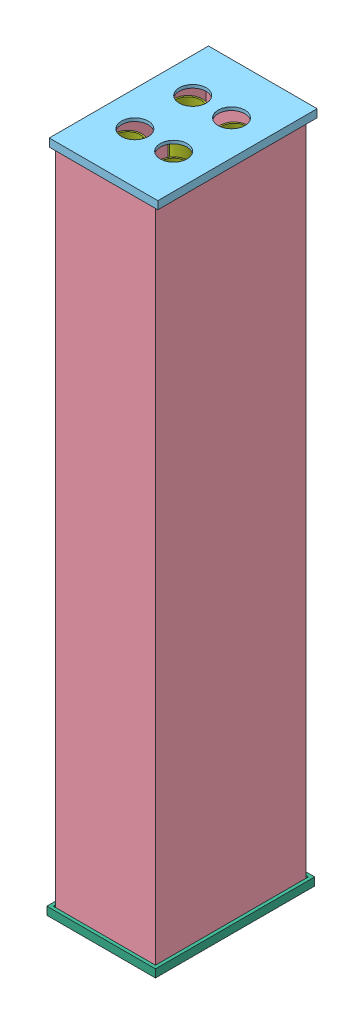
SolidWorks assembly Ensamblaje1, configuration Predeterminado. Lengths in mm.
Overall size (68.5 429 102).
50 component instances, 27 part files, 116 mates.
Components (placement in the parent):
- ServosConTubos-1: ServosConTubos [Predeterminado] at (2.491 9.9258 73.5) size (49 4 78)
- UnionTubos-1: UnionTubos [Predeterminado] at (2.491 9.9258 75.55) x (-1 0 0) z (0 0 1) size (49 40.94 58.1)
- Servo-1: Servo [Predeterminado] at (2.741 -2.0742 52.75) size (12 30.1 32.5)
- Servo-2: Servo [Predeterminado] at (2.741 -2.0742 91.25) size (12 30.1 32.5)
- Acrilico-1: Acrilico [Predeterminado] at (1.741 -24.0149 74.8) x (-1 0 0) z (0 0 -1) size (63 420 95) (hidden)
- ServosConTubos-2: ServosConTubos [Predeterminado] at (2.491 75.8429 73.5) x (-1 0 0) z (0 0 1) size (49 4 78)
- Servo-3: Servo [Predeterminado] at (2.241 87.8429 52.75) x (-1 0 0) z (0 0 1) size (12 30.1 32.5)
- Servo-4: Servo [Predeterminado] at (2.241 87.8429 91.25) x (-1 0 0) z (0 0 1) size (12 30.1 32.5)
- SoporteTubos-1: SoporteTubos [Predeterminado] at (-5.259 395.9851 62.8) size (68.5 5 100.5)
- TubosMedio-1: TubosMedio [Predeterminado] at (2.491 53.6258 73.5) size (49 2 78)
- Perno-1: Perno [Predeterminado] at (21.991 75.8429 41.5) size (8.7 78.2 8.7)
- Perno-2: Perno [Predeterminado] at (-17.009 75.8429 41.5) size (8.7 78.2 8.7)
- Perno-3: Perno [Predeterminado] at (21.991 75.8429 109.5) x (0.404197 0 -0.914672) z (0.914672 0 0.404197) size (8.7 78.2 8.7) (hidden)
- Perno-4: Perno [Predeterminado] at (-17.009 75.8429 109.5) x (-0.888519 0 0.45884) z (-0.45884 0 -0.888519) size (8.7 78.2 8.7) (hidden)
- PastillaAmarrillaAjuste-1: PastillaAmarrillaAjuste [Predeterminado] at (-12.009 64.3429 94.6) x (0 0 1) z (-1 0 0) size (20 15.85 18)
- PernoTuerca-1: PernoTuerca [Predeterminado] at (-17.009 6.4258 41.5) x (0.998119 0 0.061298) z (-0.061298 0 0.998119) size (9.5 3.5 10.97)
- PernoTuerca-2: PernoTuerca [Predeterminado] at (21.991 6.4258 109.5) size (9.5 3.5 10.97)
- PernoTuerca-3: PernoTuerca [Predeterminado] at (-17.009 6.4258 109.5) x (0.996539 0 -0.083129) z (0.083129 0 0.996539) size (9.5 3.5 10.97)
- PernoTuerca-4: PernoTuerca [Predeterminado] at (21.991 6.4258 41.5) size (9.5 3.5 10.97)
- TuboMedioAmarrillo-1: TuboMedioAmarrillo [Predeterminado] at (-12.009 29.6258 94.6) x (0.872551 0 -0.488522) z (0.488522 0 0.872551) size (14.5 26 14.5)
- PastillaAmarrillaAjuste-2: PastillaAmarrillaAjuste [Predeterminado] at (-12.009 21.4258 94.6) x (0 0 -1) z (-1 0 0) size (20 15.85 18) (hidden)
- PastillaBlancaAjuste-2: PastillaBlancaAjuste [Predeterminado] at (16.991 21.4258 94.6) x (0 0 1) z (1 0 0) size (20 20.07 18) (hidden)
- TuboMedioBlanco-1: TuboMedioBlanco [Predeterminado] at (16.991 34.1258 94.6) x (0.999102 0 -0.042366) z (0.042366 0 0.999102) size (12.5 21.5 12.5)
- PastillaBlancaAjuste2-1: PastillaBlancaAjuste2 [Predeterminado] at (16.991 64.3429 94.6) x (0 0 -1) z (1 0 0) size (20 15.53 18)
- PastillaNaranjaAjuste-1: PastillaNaranjaAjuste [Predeterminado] at (16.991 64.3429 56.5) x (0 0 -1) z (1 0 0) size (20 15.72 18)
- TuboMedioNaranja-1: TuboMedioNaranja [Predeterminado] at (16.991 36.1258 56.5) size (15 19.5 15)
- TuboMedioAzul-1: TuboMedioAzul [Predeterminado] at (-12.009 36.1258 56.5) x (-0.835913 0 0.548862) z (-0.548862 0 -0.835913) size (13 19.5 13)
- PastillaAzulAjuste-1: PastillaAzulAjuste [Predeterminado] at (-12.009 64.3429 56.5) x (0 0 1) z (-1 0 0) size (20 15.56 18)
- PastillaAzulAjuste2-1: PastillaAzulAjuste2 [Predeterminado] at (-12.009 21.4258 56.5) x (0 0 -1) z (-1 0 0) size (20 21.94 18) (hidden)
- PastillaNaranjaAjuste2-1: PastillaNaranjaAjuste2 [Predeterminado] at (16.991 21.4258 56.5) x (0 0 1) z (1 0 0) size (20 21.97 18) (hidden)
- BrazoServo-1: BrazoServo [Predeterminado] at (2.241 60.4429 58) x (-0.995394 0 -0.095869) z (-0.095869 0 0.995394) size (32 3.7 7)
- BrazoServo-2: BrazoServo [Predeterminado] at (2.741 24.9258 96.5) x (-0.996577 0 0.082664) z (-0.082664 0 -0.996577) size (32 3.7 7)
- BrazoServo-3: BrazoServo [Predeterminado] at (2.741 24.9258 58) x (0.992133 0 0.125188) z (-0.125188 0 0.992133) size (32 3.7 7)
- BrazoServo-4: BrazoServo [Predeterminado] at (2.241 60.4429 96.5) x (0.984587 0 -0.174895) z (-0.174895 0 -0.984587) size (32 3.7 7)
- BrazoExtension-3: BrazoExtension [Predeterminado] at (-17.4422 56.7429 55.1529) x (0.999799 0 -0.020027) z (0.020027 0 0.999799) size (40.04 0.5 23.31)
- BrazoExtension_AN-2: BrazoExtension_AN [Predeterminado] at (-17.1347 27.1258 97.1992) x (0.980296 0 -0.197535) z (0.197535 0 0.980296) size (40.03 7 27.06)
- BrazoExtension-4: BrazoExtension [Predeterminado] at (-17.4838 56.2429 99.0428) x (0.957704 0 -0.287755) z (0.287755 0 0.957704) size (40.04 0.5 23.31)
- BrazoExtension_AB-1: BrazoExtension_AB [Predeterminado] at (22.5686 35.1258 59.5482) x (-0.970956 0 -0.239257) z (-0.239257 0 0.970956) size (41.06 7.5 20.68)
- TapaInferiorCaja-1: TapaInferiorCaja [Predeterminado] at (10.241 -24.0149 64.3) x (-1 0 0) z (0 0 1) size (68.5 5 100.5)
- tuboreserva-1: tuboreserva [Predeterminado] at (-12.009 75.8429 56.5) x (0.395358 0 -0.918527) z (0.918527 0 0.395358) size (18 315 18)
- tuboreserva-2: tuboreserva [Predeterminado] at (-12.009 75.8429 94.6) x (0.85234 0 -0.522988) z (0.522988 0 0.85234) size (18 315 18)
- tuboreserva-3: tuboreserva [Predeterminado] at (16.991 75.8429 56.5) x (0.294164 0 -0.955755) z (0.955755 0 0.294164) size (18 315 18)
- tuboreserva-4: tuboreserva [Predeterminado] at (16.991 75.8429 94.6) x (0.996074 0 -0.088521) z (0.088521 0 0.996074) size (18 315 18)
- PillWhite-1: PillWhite [Predeterminado] at (16.991 34.1258 94.6) size (8 21.5 8)
- PillWhite-2: PillWhite [Predeterminado] at (16.991 57.9579 94.6) x (0.469176 0 -0.883105) z (0.883105 0 0.469176) size (8 21.5 8)
- PillWhite-3: PillWhite [Predeterminado] at (16.991 80.4668 94.6) x (-0.034787 0 -0.999395) z (0.999395 0 -0.034787) size (8 21.5 8)
- PillWhite-4: PillWhite [Predeterminado] at (16.991 104.123 94.6) x (-0.952143 0 -0.305654) z (0.305654 0 -0.952143) size (8 21.5 8)
- PillOrange-1: PillOrange [Predeterminado] at (-12.009 29.6499 94.6) x (0.911188 0 -0.411991) z (0.411991 0 0.911188) size (10 26 10)
- PillOrange-2: PillOrange [Predeterminado] at (-12.009 58.1552 94.6) x (0.748351 0 -0.663302) z (0.663302 0 0.748351) size (10 26 10)
- PillOrange-3: PillOrange [Predeterminado] at (-12.009 84.5081 94.6) x (0.688453 0 -0.725281) z (0.725281 0 0.688453) size (10 26 10)
Mates (geometry in assembly coordinates):
- Coincidente3: coincident: plane of assembly; plane of assembly; plane of ServosConTubos-1 through (2.491 9.9258 73.5) normal (0 -1 0); plane of UnionTubos-1 through (-12.009 9.9258 56.5) normal (0 1 0)
- Concéntrica2: concentric: cylinder of assembly; cylinder of assembly; cylinder of ServosConTubos-1 through (16.991 13.9258 94.6) axis (0 -1 0) radius 8; cylinder of UnionTubos-1 through (16.991 7.9258 94.6) axis (0 1 0) radius 8
- Concéntrica3: concentric: cylinder of assembly; cylinder of assembly; cylinder of ServosConTubos-1 through (16.991 13.9258 56.5) axis (0 -1 0) radius 8; cylinder of UnionTubos-1 through (16.991 7.9258 56.5) axis (0 1 0) radius 8
- Coincidente4: coincident: plane of assembly; plane of assembly; plane of ServosConTubos-1 through (-3.759 13.9258 102.5) normal (0 0 -1); plane of Servo-2 through (8.741 20.4258 102.5) normal (0 0 1)
- Coincidente5: coincident: plane of assembly; plane of assembly; plane of ServosConTubos-1 through (2.491 13.9258 73.5) normal (0 1 0); plane of Servo-2 through (-8.8492 13.9258 102.5) normal (0 -1 0)
- Coincidente6: coincident: plane of assembly; plane of assembly; plane of ServosConTubos-1 through (8.741 13.9258 79.6) normal (-1 0 0); plane of Servo-2 through (8.741 20.4258 80) normal (1 0 0)
- Coincidente7: coincident: plane of assembly; plane of assembly; plane of ServosConTubos-1 through (8.741 13.9258 41.5) normal (-1 0 0); plane of Servo-1 through (8.741 20.4258 41.5) normal (1 0 0)
- Coincidente8: coincident: plane of assembly; plane of assembly; plane of ServosConTubos-1 through (8.741 13.9258 41.5) normal (0 0 1); plane of Servo-1 through (8.741 20.4258 41.5) normal (0 0 -1)
- Coincidente9: coincident: plane of assembly; plane of assembly; plane of Servo-1 through (-8.8492 16.4258 64) normal (0 1 0); plane of Servo-2 through (-8.8492 16.4258 80) normal (0 1 0)
- Coincidente13: coincident: plane of assembly; plane of assembly; plane of ServosConTubos-2 through (-3.759 71.8429 79.6) normal (1 0 0); plane of Servo-4 through (-3.759 65.3429 80) normal (-1 0 0)
- Coincidente14: coincident: plane of assembly; plane of assembly; plane of ServosConTubos-2 through (8.741 71.8429 102.5) normal (0 0 -1); plane of Servo-4 through (-3.759 65.3429 102.5) normal (0 0 1)
- Coincidente15: coincident: plane of assembly; plane of assembly; plane of ServosConTubos-2 through (2.491 71.8429 73.5) normal (0 -1 0); plane of Servo-4 through (13.8311 71.8429 102.5) normal (0 1 0)
- Coincidente16: coincident: plane of assembly; plane of assembly; plane of ServosConTubos-2 through (-3.759 71.8429 41.5) normal (1 0 0); plane of Servo-3 through (-3.759 65.3429 41.5) normal (-1 0 0)
- Coincidente17: coincident: plane of assembly; plane of assembly; plane of ServosConTubos-2 through (-3.759 71.8429 41.5) normal (0 0 1); plane of Servo-3 through (-3.759 65.3429 41.5) normal (0 0 -1)
- Coincidente18: coincident: plane of assembly; plane of assembly; plane of ServosConTubos-2 through (2.491 71.8429 73.5) normal (0 -1 0); plane of Servo-3 through (13.8311 71.8429 41.5) normal (0 1 0)
- Coincidente21: coincident: plane of assembly; plane of assembly; plane of ServosConTubos-1 through (-22.009 -39.3287 114.5) normal (0 0 1); plane of ServosConTubos-2 through (26.991 125.0974 114.5) normal (0 0 1)
- Coincidente22: coincident: plane of assembly; plane of assembly; plane of ServosConTubos-1 through (-22.009 13.9258 36.5) normal (-1 0 0); plane of ServosConTubos-2 through (-22.009 71.8429 36.5) normal (-1 0 0)
- Coincidente29: coincident: plane of assembly; plane of assembly; plane of ServosConTubos-1 through (-22.009 13.9258 36.5) normal (-1 0 0); plane of TubosMedio-1 through (-22.009 55.6258 36.5) normal (-1 0 0)
- Coincidente30: coincident: plane of assembly; plane of assembly; plane of ServosConTubos-1 through (-22.009 13.9258 36.5) normal (0 0 -1); plane of TubosMedio-1 through (-22.009 55.6258 36.5) normal (0 0 -1)
- Concéntrica4: concentric: cylinder of assembly; cylinder of assembly; cylinder of ServosConTubos-2 through (21.991 71.8429 41.5) axis (0 1 0) radius 2.5; cylinder of Perno-1 through (21.991 1.8429 41.5) axis (0 1 0) radius 2.35
- Concéntrica5: concentric: cylinder of assembly; cylinder of assembly; cylinder of ServosConTubos-2 through (-17.009 71.8429 41.5) axis (0 1 0) radius 2.5; cylinder of Perno-2 through (-17.009 1.8429 41.5) axis (0 1 0) radius 2.35
- Concéntrica6: concentric: cylinder of assembly; cylinder of assembly; cylinder of ServosConTubos-2 through (21.991 81.8429 109.5) axis (0 -1 0) radius 2.5; cylinder of Perno-3 through (21.991 1.8429 109.5) axis (0 1 0) radius 2.35
- Concéntrica7: concentric: circle of assembly; cylinder of assembly; circle of ServosConTubos-2; cylinder of Perno-4 through (-17.009 1.8429 109.5) axis (0 1 0) radius 2.35
- Coincidente31: coincident: plane of assembly; plane of assembly; plane of Perno-3 through (21.991 75.8429 109.5) normal (0 -1 0); plane of Perno-4 through (-17.009 75.8429 109.5) normal (0 -1 0)
- Coincidente32: coincident: plane of assembly; plane of assembly; plane of Perno-2 through (-17.009 75.8429 41.5) normal (0 -1 0); plane of Perno-4 through (-17.009 75.8429 109.5) normal (0 -1 0)
- Coincidente33: coincident: plane of assembly; plane of assembly; plane of Perno-1 through (21.991 75.8429 41.5) normal (0 -1 0); plane of Perno-2 through (-17.009 75.8429 41.5) normal (0 -1 0)
- Coincidente34: coincident: plane of assembly; plane of assembly; plane of ServosConTubos-2 through (2.491 75.8429 73.5) normal (0 1 0); plane of Perno-1 through (21.991 75.8429 41.5) normal (0 -1 0)
- Coincidente35: coincident: cylinder of assembly; circle of assembly; cylinder of ServosConTubos-2 through (-12.009 71.8429 94.6) axis (0 1 0) radius 8; circle of PastillaAmarrillaAjuste-1
- Coincidente36: coincident: plane of assembly; plane of assembly; plane of ServosConTubos-2 through (2.491 71.8429 73.5) normal (0 -1 0); plane of PastillaAmarrillaAjuste-1 through (-12.009 71.8429 86.6) normal (0 1 0)
- Concéntrica8: concentric: cylinder of assembly; cylinder of assembly; cylinder of Perno-2 through (-17.009 1.8429 41.5) axis (0 1 0) radius 2.35; cylinder of PernoTuerca-1 through (-17.009 9.9258 41.5) axis (0 -1 0) radius 2.35
- Concéntrica9: concentric: cylinder of assembly; cylinder of assembly; cylinder of Perno-4 through (-17.009 1.8429 109.5) axis (0 1 0) radius 2.35; cylinder of PernoTuerca-3 through (-17.009 9.9258 109.5) axis (0 -1 0) radius 2.35
- Coincidente37: coincident: plane of assembly; plane of assembly; plane of PernoTuerca-1 through (-17.009 9.9258 41.5) normal (0 1 0); plane of PernoTuerca-3 through (-17.009 9.9258 109.5) normal (0 1 0)
- Concéntrica10: concentric: cylinder of assembly; cylinder of assembly; cylinder of Perno-3 through (21.991 1.8429 109.5) axis (0 1 0) radius 2.35; cylinder of PernoTuerca-2 through (21.991 9.9258 109.5) axis (0 -1 0) radius 2.35
- Coincidente38: coincident: plane of assembly; plane of assembly; plane of PernoTuerca-2 through (21.991 9.9258 109.5) normal (0 1 0); plane of PernoTuerca-3 through (-17.009 9.9258 109.5) normal (0 1 0)
- Concéntrica11: concentric: cylinder of assembly; cylinder of assembly; cylinder of Perno-1 through (21.991 1.8429 41.5) axis (0 1 0) radius 2.35; cylinder of PernoTuerca-4 through (21.991 9.9258 41.5) axis (0 -1 0) radius 2.35
- Coincidente39: coincident: plane of assembly; plane of assembly; plane of PernoTuerca-1 through (-17.009 9.9258 41.5) normal (0 1 0); plane of PernoTuerca-4 through (21.991 9.9258 41.5) normal (0 1 0)
- Concéntrica12: concentric: cylinder of PastillaAmarrillaAjuste-1 through (-12.009 56.8429 94.6) axis (0 1 0) radius 7.25; cylinder of ? through (-12.009 55.6258 94.6) axis (0 -1 0) radius 7.25
- Coincidente43: coincident: plane of assembly; plane of assembly; plane of ServosConTubos-1 through (2.491 13.9258 73.5) normal (0 1 0); plane of PastillaAmarrillaAjuste-2 through (-12.009 13.9258 102.6) normal (0 -1 0)
- Concéntrica13: concentric: cylinder of ? through (-12.009 55.6258 94.6) axis (0 -1 0) radius 7.25; cylinder of PastillaAmarrillaAjuste-2 through (-12.009 28.9258 94.6) axis (0 -1 0) radius 7.25
- Coincidente44: coincident: plane of assembly; plane of assembly; plane of ServosConTubos-1 through (2.491 9.9258 73.5) normal (0 -1 0); plane of PernoTuerca-1 through (-17.009 9.9258 41.5) normal (0 1 0)
- Concéntrica15: concentric: cylinder of assembly; cylinder of assembly; cylinder of TubosMedio-1 through (16.991 55.6258 94.6) axis (0 -1 0) radius 5.25; cylinder of PastillaBlancaAjuste-2 through (16.991 33.4258 94.6) axis (0 -1 0) radius 6.25
- Coincidente49: coincident: plane of assembly; plane of assembly; plane of ServosConTubos-1 through (2.491 13.9258 73.5) normal (0 1 0); plane of PastillaBlancaAjuste-2 through (16.991 13.9258 86.6) normal (0 -1 0)
- Concéntrica16: concentric: cylinder of PastillaBlancaAjuste-2 through (16.991 33.4258 94.6) axis (0 -1 0) radius 6.25; cylinder of ? through (16.991 55.6258 94.6) axis (0 -1 0) radius 6.25
- Concéntrica17: concentric: cylinder of ? through (16.991 55.6258 94.6) axis (0 -1 0) radius 6.25; cylinder of PastillaBlancaAjuste2-1 through (16.991 56.8429 94.6) axis (0 1 0) radius 6.25
- Coincidente51: coincident: plane of assembly; plane of assembly; plane of ServosConTubos-2 through (2.491 71.8429 73.5) normal (0 -1 0); plane of PastillaBlancaAjuste2-1 through (16.991 71.8429 102.6) normal (0 1 0)
- Concéntrica18: concentric: cylinder of assembly; cylinder of assembly; cylinder of ServosConTubos-2 through (16.991 71.8429 56.5) axis (0 1 0) radius 8; cylinder of PastillaNaranjaAjuste-1 through (16.991 56.8429 56.5) axis (0 1 0) radius 7.5
- Coincidente52: coincident: plane of assembly; plane of assembly; plane of ServosConTubos-2 through (2.491 71.8429 73.5) normal (0 -1 0); plane of PastillaNaranjaAjuste-1 through (16.991 71.8429 64.5) normal (0 1 0)
- Concéntrica19: concentric: cylinder of PastillaNaranjaAjuste-1 through (16.991 56.8429 56.5) axis (0 1 0) radius 7.5; cylinder of ? through (16.991 55.6258 56.5) axis (0 -1 0) radius 7.5
- Coincidente53: coincident: plane of ? through (16.991 55.6258 94.6) normal (0 1 0); plane of ? through (16.991 55.6258 56.5) normal (0 1 0)
- Concéntrica20: concentric: cylinder of TubosMedio-1 through (-12.009 55.6258 56.5) axis (0 -1 0) radius 4.25; cylinder of ? through (-12.009 55.6258 56.5) axis (0 -1 0) radius 6.5
- Coincidente54: coincident: plane of ? through (16.991 55.6258 56.5) normal (0 1 0); plane of ? through (-12.009 55.6258 56.5) normal (0 1 0)
- Concéntrica21: concentric: cylinder of ? through (-12.009 55.6258 56.5) axis (0 -1 0) radius 6.5; cylinder of PastillaAzulAjuste-1 through (-12.009 56.8429 56.5) axis (0 1 0) radius 6.5
- Coincidente55: coincident: plane of assembly; plane of assembly; plane of ServosConTubos-2 through (2.491 71.8429 73.5) normal (0 -1 0); plane of PastillaAzulAjuste-1 through (-12.009 71.8429 48.5) normal (0 1 0)
- Coincidente56: coincident: plane of assembly; plane of assembly; plane of ServosConTubos-1 through (2.491 13.9258 73.5) normal (0 1 0); plane of PastillaNaranjaAjuste2-1 through (16.991 13.9258 48.5) normal (0 -1 0)
- Concéntrica22: concentric: cylinder of assembly; cylinder of assembly; cylinder of ServosConTubos-1 through (16.991 13.9258 56.5) axis (0 -1 0) radius 8; cylinder of PastillaNaranjaAjuste2-1 through (16.991 35.4258 56.5) axis (0 -1 0) radius 7.25
- Coincidente57: coincident: plane of assembly; plane of assembly; plane of ServosConTubos-1 through (2.491 13.9258 73.5) normal (0 1 0); plane of PastillaAzulAjuste2-1 through (-12.009 13.9258 64.5) normal (0 -1 0)
- Concéntrica23: concentric: cylinder of assembly; cylinder of assembly; cylinder of ServosConTubos-1 through (-12.009 13.9258 56.5) axis (0 -1 0) radius 8; cylinder of PastillaAzulAjuste2-1 through (-12.009 35.4258 56.5) axis (0 -1 0) radius 4.5
- Paralelo1: parallel: plane of assembly; plane of assembly; plane of Servo-1 through (8.741 20.4258 41.5) normal (1 0 0); plane of PastillaNaranjaAjuste2-1 through (8.991 23.9258 49.0202) normal (-1 0 0)
- Paralelo2: parallel: plane of assembly; plane of assembly; plane of Servo-1 through (-3.259 20.4258 41.5) normal (-1 0 0); plane of PastillaAzulAjuste2-1 through (-4.009 21.4258 63.6123) normal (1 0 0)
- Paralelo3: parallel: plane of assembly; plane of assembly; plane of Servo-3 through (8.241 65.3429 41.5) normal (1 0 0); plane of PastillaNaranjaAjuste-1 through (8.991 52.3429 63.8008) normal (-1 0 0)
- Paralelo4: parallel: plane of assembly; plane of assembly; plane of Servo-3 through (-3.759 65.3429 41.5) normal (-1 0 0); plane of PastillaAzulAjuste-1 through (-4.009 64.3429 47.4722) normal (1 0 0)
- Paralelo5: parallel: plane of assembly; plane of assembly; plane of Servo-4 through (-3.759 65.3429 80) normal (-1 0 0); plane of PastillaAmarrillaAjuste-1 through (-4.009 64.3429 85.9959) normal (1 0 0)
- Paralelo6: parallel: plane of assembly; plane of assembly; plane of Servo-2 through (-3.259 20.4258 80) normal (-1 0 0); plane of PastillaAmarrillaAjuste-2 through (-4.009 21.4258 103.2041) normal (1 0 0)
- Paralelo7: parallel: plane of assembly; plane of assembly; plane of Servo-4 through (8.241 65.3429 80) normal (1 0 0); plane of PastillaBlancaAjuste2-1 through (8.991 61.8429 102.4165) normal (-1 0 0)
- Paralelo8: parallel: plane of assembly; plane of assembly; plane of Servo-2 through (8.741 20.4258 80) normal (1 0 0); plane of PastillaBlancaAjuste-2 through (8.991 23.9258 83.6229) normal (-1 0 0)
- Coincidente58: coincident: plane of assembly; plane of assembly; plane of Servo-3 through (2.241 57.7429 58) normal (0 -1 0); plane of BrazoServo-1 through (16.3258 57.7429 59.3565) normal (0 1 0)
- Concéntrica24: concentric: cylinder of assembly; cylinder of assembly; cylinder of Servo-3 through (2.241 57.7429 58) axis (0 1 0) radius 2.4; cylinder of BrazoServo-1 through (2.241 56.7429 58) axis (0 1 0) radius 3.5
- Coincidente59: coincident: plane of Servo-4 through (2.241 57.7429 96.5) normal (0 -1 0); plane of ? through (-9.6917 57.7429 104.1049) normal (0 1 0)
- Concéntrica25: concentric: cylinder of Servo-4 through (2.241 57.7429 96.5) axis (0 1 0) radius 2.4; cylinder of ? through (2.241 56.7429 96.5) axis (0 1 0) radius 3.5
- Coincidente68: coincident: plane of assembly; plane of assembly; plane of BrazoServo-1 through (2.241 56.7429 58) normal (0 -1 0); plane of BrazoExtension-3 through (-4.9747 56.7429 54.9032) normal (0 -1 0)
- Concéntrica30: concentric: cylinder of Servo-2 through (2.741 28.0258 96.5) axis (0 -1 0) radius 2.4; cylinder of ? through (2.741 28.6258 96.5) axis (0 -1 0) radius 3.5
- Coincidente72: coincident: plane of Servo-2 through (2.741 24.9258 96.5) normal (0 1 0); plane of ? through (2.741 24.9258 96.5) normal (0 -1 0)
- Concéntrica31: concentric: cylinder of ? through (2.741 28.6258 96.5) axis (0 -1 0) radius 3.5; cylinder of ? through (2.741 27.1258 96.5) axis (0 1 0) radius 4.5
- Coincidente75: coincident: circle of ?; plane of ? through (16.991 55.6258 94.6) normal (0 1 0)
- Coincidente76: coincident: plane of ? through (-12.009 55.6258 94.6) normal (0 1 0); plane of ? through (-12.009 55.6258 56.5) normal (0 1 0)
- Coincidente77: coincident: plane of ? through (16.991 55.6258 94.6) normal (0 1 0); plane of ? through (16.991 55.6258 56.5) normal (0 1 0)
- Coincidente78: coincident: plane of TubosMedio-1 through (2.491 55.6258 73.5) normal (0 1 0); plane of ? through (-12.009 55.6258 94.6) normal (0 1 0)
- DISTANCIA8: distance = 1 mm: plane of assembly; plane of assembly; plane of BrazoServo-2 through (2.741 28.6258 96.5) normal (0 1 0); plane of TuboMedioAmarrillo-1 through (-12.009 29.6258 94.6) normal (0 -1 0)
- Concéntrica32: concentric: cylinder of assembly; cylinder of assembly; cylinder of BrazoServo-1 through (2.241 56.7429 58) axis (0 1 0) radius 3.5; cylinder of BrazoExtension-3 through (2.241 56.7429 58) axis (0 1 0) radius 4
- Coincidente81: coincident: plane of assembly; plane of assembly; plane of BrazoServo-1 through (-12.0212 57.7429 58.4849) normal (-0.210513 0 0.977591); plane of BrazoExtension-3 through (-17.8876 56.7429 57.2217) normal (-0.210513 0 0.977591)
- Paralelo13: parallel: plane of ? through (-5.3511 56.7429 98.5039) normal (0 1 0); plane of ? through (2.241 56.7429 96.5) normal (0 -1 0)
- Concéntrica33: concentric: cylinder of ? through (2.241 56.7429 96.5) axis (0 1 0) radius 3.5; cylinder of ? through (2.241 56.2429 96.5) axis (0 1 0) radius 4
- Coincidente83: coincident: plane of ? through (4.122 57.7429 99.4515) normal (0.631502 0 0.775375); plane of ? through (-10.7782 56.2429 111.587) normal (0.631502 0 0.775375)
- Coincidente84: coincident: plane of ? through (2.241 56.7429 96.5) normal (0 -1 0); plane of ? through (-5.3511 56.7429 98.5039) normal (0 1 0)
- Paralelo15: parallel: plane of ? through (16.7004 27.6258 99.4629) normal (0.036936 0 0.999318); plane of ? through (-16.7431 27.6258 100.5996) normal (0.036936 0 0.999318)
- Concéntrica34: concentric: cylinder of assembly; cylinder of assembly; cylinder of Servo-1 through (2.741 28.0258 58) axis (0 -1 0) radius 2.4; cylinder of BrazoServo-3 through (2.741 28.6258 58) axis (0 -1 0) radius 3.5
- Coincidente90: coincident: plane of Servo-1 through (2.741 24.9258 58) normal (0 1 0); plane of BrazoServo-3 through (2.741 24.9258 58) normal (0 -1 0)
- Coincidente91: coincident: plane of BrazoServo-3 through (2.741 28.6258 58) normal (0 1 0); plane of BrazoExtension_AB-1 through (22.5686 28.6258 59.5482) normal (0 -1 0)
- Paralelo17: parallel: plane of BrazoServo-3 through (2.3028 27.6258 61.4725) normal (-0.239257 0 0.970956); plane of BrazoExtension_AB-1 through (20.9852 34.6258 65.9738) normal (-0.239257 0 0.970956)
- Concéntrica35: concentric: cylinder of BrazoServo-3 through (2.741 28.6258 58) axis (0 -1 0) radius 3.5; cylinder of BrazoExtension_AB-1 through (2.741 34.6258 58) axis (0 1 0) radius 1.5
- Paralelo18: parallel: plane of assembly; plane of assembly; plane of ServosConTubos-1 through (-22.009 13.9258 36.5) normal (0 0 -1); plane of Acrilico-1 through (-29.759 395.9851 27.3) normal (0 0 -1)
- Paralelo19: parallel: plane of Acrilico-1 through (33.241 395.9851 122.3) normal (1 0 0); plane of ServosConTubos-2 through (26.991 71.8429 36.5) normal (1 0 0)
- Coincidente94: coincident: plane of Acrilico-1 through (-29.759 395.9851 122.3) normal (-1 0 0); plane of SoporteTubos-1 through (-29.759 519.6096 122.3) normal (1 0 0)
- Coincidente95: coincident: plane of Acrilico-1 through (-29.759 395.9851 122.3) normal (0 0 1); plane of SoporteTubos-1 through (-29.759 519.6096 122.3) normal (0 0 -1)
- Coincidente96: coincident: plane of Acrilico-1 through (1.741 395.9851 74.8) normal (0 1 0); plane of SoporteTubos-1 through (-5.259 395.9851 62.8) normal (0 -1 0)
- Coincidente97: coincident: plane of Acrilico-1 through (1.741 -24.0149 74.8) normal (0 -1 0); plane of TapaInferiorCaja-1 through (10.241 -24.0149 64.3) normal (0 1 0)
- Coincidente98: coincident: plane of Acrilico-1 through (-29.759 395.9851 27.3) normal (0 0 -1); plane of TapaInferiorCaja-1 through (34.741 -147.6393 27.3) normal (0 0 1)
- Coincidente99: coincident: plane of Acrilico-1 through (-29.759 395.9851 122.3) normal (-1 0 0); plane of TapaInferiorCaja-1 through (-29.759 -147.6393 123.8) normal (1 0 0)
- Concéntrica36: concentric: cylinder of UnionTubos-1 through (2.491 21.9116 75.55) axis (0 -1 0) radius 15; cylinder of TapaInferiorCaja-1 through (2.491 -26.0149 75.55) axis (0 1 0) radius 16
- Distancia9: distance = 5 mm: plane of TapaInferiorCaja-1 through (10.241 -26.0149 64.3) normal (0 -1 0); plane of UnionTubos-1 through (2.491 -31.0149 75.55) normal (0 -1 0)
- Concéntrica37: concentric: cylinder of assembly; cylinder of assembly; cylinder of ServosConTubos-2 through (16.991 71.8429 94.6) axis (0 1 0) radius 8; cylinder of tuboreserva-4 through (16.991 390.8429 94.6) axis (0 -1 0) radius 9
- Concéntrica38: concentric: cylinder of assembly; cylinder of assembly; cylinder of ServosConTubos-2 through (-12.009 71.8429 56.5) axis (0 1 0) radius 8; cylinder of tuboreserva-1 through (-12.009 390.8429 56.5) axis (0 -1 0) radius 9
- Concéntrica39: concentric: cylinder of assembly; cylinder of assembly; cylinder of ServosConTubos-2 through (16.991 71.8429 56.5) axis (0 1 0) radius 8; cylinder of tuboreserva-3 through (16.991 390.8429 56.5) axis (0 -1 0) radius 9
- Concéntrica40: concentric: cylinder of assembly; cylinder of assembly; cylinder of ServosConTubos-2 through (-12.009 71.8429 94.6) axis (0 1 0) radius 8; cylinder of tuboreserva-2 through (-12.009 390.8429 94.6) axis (0 -1 0) radius 9
- Coincidente100: coincident: plane of ServosConTubos-2 through (2.491 75.8429 73.5) normal (0 1 0); plane of tuboreserva-2 through (-12.009 75.8429 94.6) normal (0 -1 0)
- Coincidente101: coincident: plane of ServosConTubos-2 through (2.491 75.8429 73.5) normal (0 1 0); plane of tuboreserva-1 through (-12.009 75.8429 56.5) normal (0 -1 0)
- Coincidente102: coincident: plane of ServosConTubos-2 through (2.491 75.8429 73.5) normal (0 1 0); plane of tuboreserva-4 through (16.991 75.8429 94.6) normal (0 -1 0)
- Coincidente103: coincident: plane of ServosConTubos-2 through (2.491 75.8429 73.5) normal (0 1 0); plane of tuboreserva-3 through (16.991 75.8429 56.5) normal (0 -1 0)
- Concéntrica41: concentric: cylinder of ? through (16.991 55.6258 94.6) axis (0 -1 0) radius 6.25; cylinder of ? through (16.991 10.8382 94.6) axis (0 -1 0) radius 4
- Concéntrica42: concentric: cylinder of PastillaBlancaAjuste2-1 through (16.991 56.8429 94.6) axis (0 1 0) radius 6.25; cylinder of ? through (16.991 56.3037 94.6) axis (0 -1 0) radius 4
- Concéntrica43: concentric: cylinder of tuboreserva-4 through (16.991 390.8429 94.6) axis (0 -1 0) radius 9; cylinder of ? through (16.991 78.6332 94.6) axis (0 -1 0) radius 4
- Concéntrica45: concentric: cylinder of tuboreserva-4 through (16.991 390.8429 94.6) axis (0 -1 0) radius 9; cylinder of ? through (16.991 100.7264 94.6) axis (0 -1 0) radius 4
- Concéntrica46: concentric: cylinder of tuboreserva-2 through (-12.009 390.8429 94.6) axis (0 -1 0) radius 9; cylinder of ? through (-12.009 82.2613 94.6) axis (0 -1 0) radius 5
- Concéntrica47: concentric: cylinder of tuboreserva-2 through (-12.009 390.8429 94.6) axis (0 -1 0) radius 9; cylinder of ? through (-12.009 54.8665 94.6) axis (0 -1 0) radius 5
- Concéntrica48: concentric: cylinder of ? through (-12.009 55.6258 94.6) axis (0 -1 0) radius 7.25; cylinder of ? through (-12.009 11.239 94.6) axis (0 -1 0) radius 5
- Coincidente105: coincident: plane of ? through (16.8467 27.6258 97.6186) normal (0 -1 0); plane of ? through (-4.526 27.6258 93.5257) normal (0 1 0)
